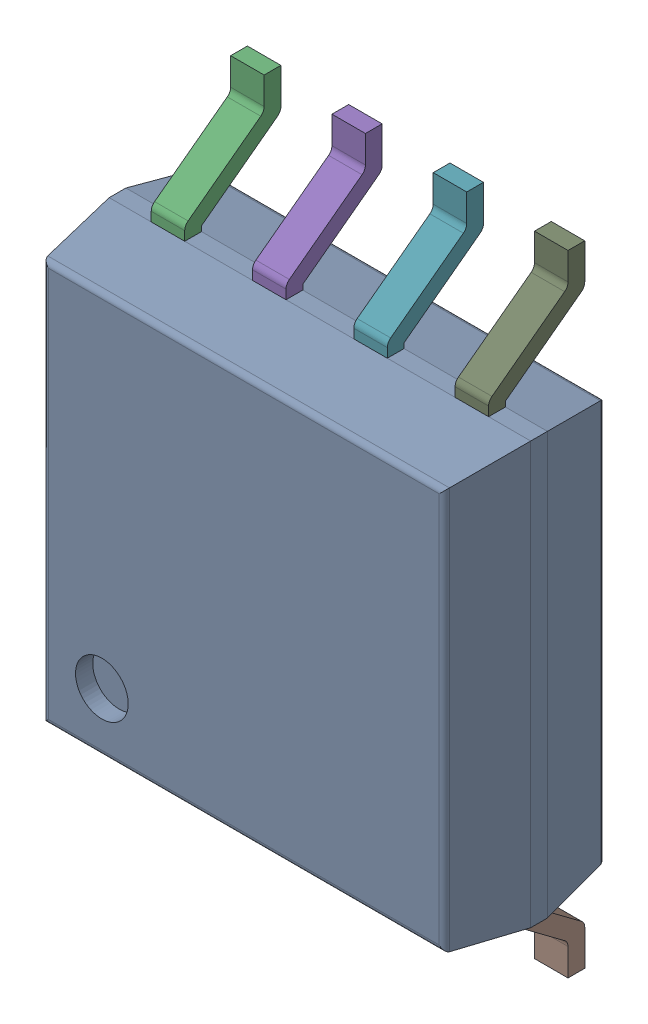
SolidWorks assembly IC6_1.step, configuration Default. Lengths in mm.
Overall size (5.29 7.9 2.16).
3 component instances, 2 part files, 0 mates.
Components (placement in the parent):
- 6348792448_1.step-11: 6348792448_1.step [Default] at (368.3196 283.055 0) x (0 1 0) z (0 0 1) size (7.9 5.29 2.16)
  - Body-12_1.step-21: Body-12_1.step [Default] at origin size (5.29 5.29 2.01)
  - PinsArrayLR-13_1.step-21: PinsArrayLR-13_1.step [Default] at origin size (7.9 4.23 1.21)
